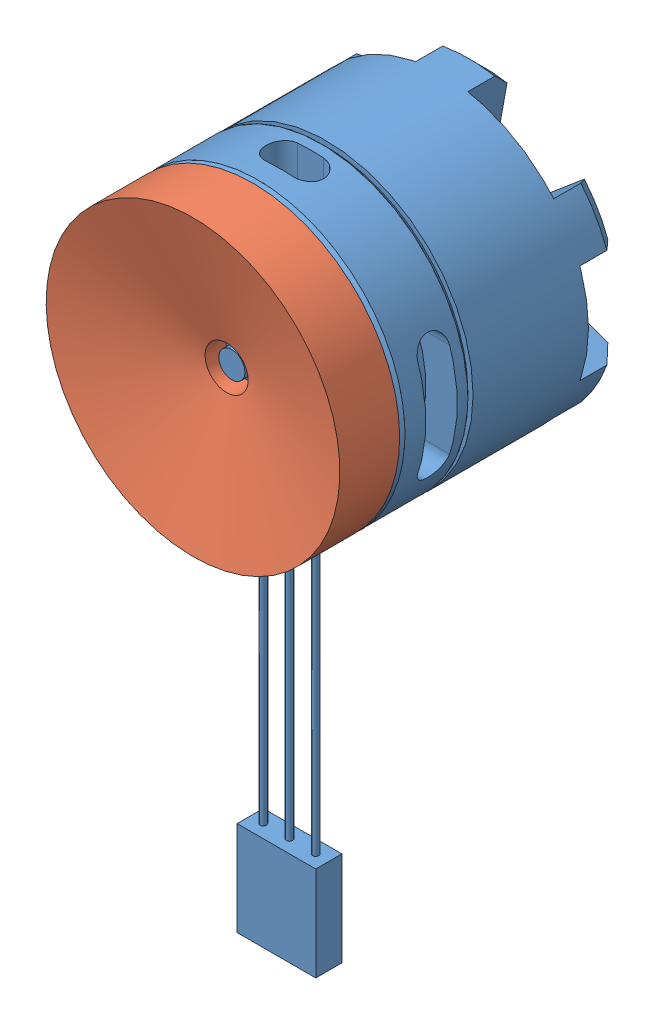
SolidWorks assembly 电机测试, configuration 默认. Lengths in mm.
Overall size (39.6 70.69 29.6).
4 component instances, 4 part files, 10 mates.
Components (placement in the parent):
- Motor2206-1: Motor2206 [默认] at (-0.7392 0.0644 -0.1415) size (28 64.89 25.9)
- 测试底座-1: 测试底座 [默认] at (-0.7392 0.0644 6.8585) x (0.707107 -0.707107 0) z (0 0 1) size (28 28 6) (hidden)
- 编码器-1: 编码器 [默认] at (-0.7392 0.0644 14.4585) x (1 0 0) z (0 0 -1) size (26 22 7.42) (hidden)
- 辅助-1: 辅助 [默认] at (-0.7392 0.0644 6.8585) x (0.707107 0.707107 0) z (0 0 1) size (28 28 7.2)
Mates (geometry in assembly coordinates):
- 重合1: coincident anti-aligned: plane of Motor2206-1 through (-0.7392 0.0644 6.8585) normal (0 0 1); plane of 测试底座-1 through (-0.7392 0.0644 6.8585) normal (0 0 -1)
- 同心1: concentric aligned: circle of Motor2206-1; circle of 测试底座-1
- 同心2: concentric aligned: circle of Motor2206-1; circle of 测试底座-1
- 同心3: concentric aligned: circle of Motor2206-1; circle of 测试底座-1
- 重合4: coincident anti-aligned: plane of 测试底座-1 through (-0.7392 0.0644 12.8585) normal (0 0 1); plane of 编码器-1 through (10.988 -1.7987 12.8585) normal (0 0 -1)
- 同心4: concentric anti-aligned: circle of 测试底座-1; circle of 编码器-1
- 同心6: concentric anti-aligned: circle of 测试底座-1; circle of 编码器-1
- 重合8: coincident anti-aligned: plane of Motor2206-1 through (-0.7392 0.0644 6.8585) normal (0 0 1); plane of 辅助-1 through (-0.7392 0.0644 6.8585) normal (0 0 -1)
- 同心7: concentric anti-aligned: circle of Motor2206-1; circle of 辅助-1
- 同心8: concentric anti-aligned: circle of Motor2206-1; circle of 辅助-1
